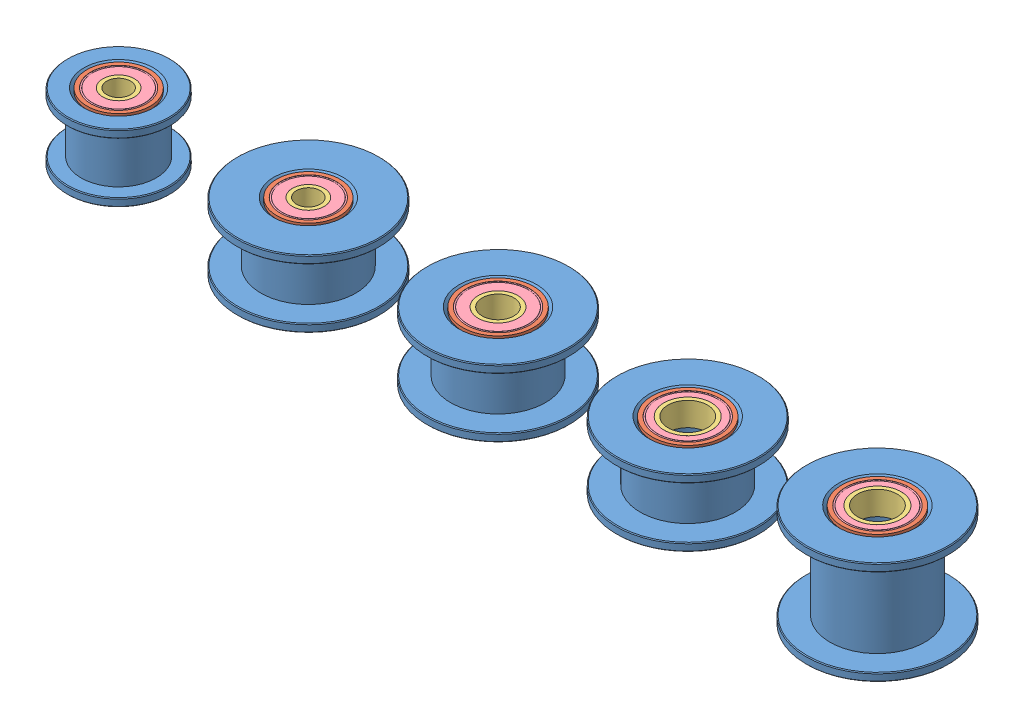
SolidWorks assembly GT2 Idler Pulley, Configurable, Pulleys Lined Up in Assembly, configuration Default. Lengths in mm.
Overall size (117.8 13 25.32).
148 component instances, 5 part files, 0 mates.
Components (placement in the parent):
- GT2 Idler Pulley, Configurable-1: GT2 Idler Pulley, Configurable [16T W6 B3 Without T] at (3.9723 -1.1239 -1.3326) size (18.29 8.5 18.29)
  - Body, GT2 Idler Pulley, Configurable-1: Body, GT2 Idler Pulley, Configurable [16T W6 B3 Without T] x (-0.63029 0 -0.77636) z (0.77636 0 -0.63029) size (13 8.5 13)
  - Bearing Subassy, GT2 Idler Pulley, Configurable-1: Bearing Subassy, GT2 Idler Pulley, Configurable [3 mm Bore] at (0 2.25 0) x (0.63029 0 0.77636) z (-0.77636 0 0.63029) size (8 4 8) (flexible)
    - Bearing Outer Ring, GT2 Idler Pulley, Configurable-1: Bearing Outer Ring, GT2 Idler Pulley, Configurable [3 mm Bore] at origin size (8 4 8)
    - Bearing Inner Ring, GT2 Idler Pulley, Configurable-1: Bearing Inner Ring, GT2 Idler Pulley, Configurable [3 mm Bore] x (0.926062 0 -0.377371) z (0.377371 0 0.926062) size (4 4 4)
    - Bearing Seal, GT2 Idler Pulley, Configurable-1: Bearing Seal, GT2 Idler Pulley, Configurable [3 mm Bore] at (0 1.75 0) size (7 0.5 7)
    - Bearing Seal, GT2 Idler Pulley, Configurable-2: Bearing Seal, GT2 Idler Pulley, Configurable [3 mm Bore] at (0 -1.75 0) x (1 0 0) z (0 0 -1) size (7 0.5 7)
    - Bearing Ball, GT2 Idler Pulley, Configurable-1: Bearing Ball, GT2 Idler Pulley, Configurable [2 mm] at (-1.9442 0 -1.9449) x (-0.715461 0 0.698652) z (-0.698652 0 -0.715461) size (2 2 2)
    - Bearing Ball, GT2 Idler Pulley, Configurable-2: Bearing Ball, GT2 Idler Pulley, Configurable [2 mm] at (0.7122 0 -2.6562) x (-0.962781 0 -0.270282) z (0.270282 0 -0.962781) size (2 2 2)
    - Bearing Ball, GT2 Idler Pulley, Configurable-3: Bearing Ball, GT2 Idler Pulley, Configurable [2 mm] at (2.6564 0 -0.7113) x (-0.24732 0 -0.968934) z (0.968934 0 -0.24732) size (2 2 2)
    - Bearing Ball, GT2 Idler Pulley, Configurable-4: Bearing Ball, GT2 Idler Pulley, Configurable [2 mm] at (1.9442 0 1.9449) x (0.715461 0 -0.698652) z (0.698652 0 0.715461) size (2 2 2)
    - Bearing Ball, GT2 Idler Pulley, Configurable-5: Bearing Ball, GT2 Idler Pulley, Configurable [2 mm] at (-0.7122 0 2.6562) x (0.962781 0 0.270282) z (-0.270282 0 0.962781) size (2 2 2)
    - Bearing Ball, GT2 Idler Pulley, Configurable-6: Bearing Ball, GT2 Idler Pulley, Configurable [2 mm] at (-2.6564 0 0.7113) x (0.24732 0 0.968934) z (-0.968934 0 0.24732) size (2 2 2)
  - Bearing Subassy, GT2 Idler Pulley, Configurable-2: Bearing Subassy, GT2 Idler Pulley, Configurable [3 mm Bore] at (0 -2.25 0) x (0.63029 0 0.77636) z (0.77636 0 -0.63029) size (8 4 8) (flexible)
    - Bearing Outer Ring, GT2 Idler Pulley, Configurable-1: Bearing Outer Ring, GT2 Idler Pulley, Configurable [3 mm Bore] at origin size (8 4 8)
    - Bearing Inner Ring, GT2 Idler Pulley, Configurable-1: Bearing Inner Ring, GT2 Idler Pulley, Configurable [3 mm Bore] x (0.926062 0 -0.377371) z (0.377371 0 0.926062) size (4 4 4)
    - Bearing Seal, GT2 Idler Pulley, Configurable-1: Bearing Seal, GT2 Idler Pulley, Configurable [3 mm Bore] at (0 1.75 0) size (7 0.5 7)
    - Bearing Seal, GT2 Idler Pulley, Configurable-2: Bearing Seal, GT2 Idler Pulley, Configurable [3 mm Bore] at (0 -1.75 0) x (1 0 0) z (0 0 -1) size (7 0.5 7)
    - Bearing Ball, GT2 Idler Pulley, Configurable-1: Bearing Ball, GT2 Idler Pulley, Configurable [2 mm] at (-1.9442 0 -1.9449) x (-0.715461 0 0.698652) z (-0.698652 0 -0.715461) size (2 2 2)
    - Bearing Ball, GT2 Idler Pulley, Configurable-2: Bearing Ball, GT2 Idler Pulley, Configurable [2 mm] at (0.7122 0 -2.6562) x (-0.962781 0 -0.270282) z (0.270282 0 -0.962781) size (2 2 2)
    - Bearing Ball, GT2 Idler Pulley, Configurable-3: Bearing Ball, GT2 Idler Pulley, Configurable [2 mm] at (2.6564 0 -0.7113) x (-0.24732 0 -0.968934) z (0.968934 0 -0.24732) size (2 2 2)
    - Bearing Ball, GT2 Idler Pulley, Configurable-4: Bearing Ball, GT2 Idler Pulley, Configurable [2 mm] at (1.9442 0 1.9449) x (0.715461 0 -0.698652) z (0.698652 0 0.715461) size (2 2 2)
    - Bearing Ball, GT2 Idler Pulley, Configurable-5: Bearing Ball, GT2 Idler Pulley, Configurable [2 mm] at (-0.7122 0 2.6562) x (0.962781 0 0.270282) z (-0.270282 0 0.962781) size (2 2 2)
    - Bearing Ball, GT2 Idler Pulley, Configurable-6: Bearing Ball, GT2 Idler Pulley, Configurable [2 mm] at (-2.6564 0 0.7113) x (0.24732 0 0.968934) z (-0.968934 0 0.24732) size (2 2 2)
- GT2 Idler Pulley, Configurable-3: GT2 Idler Pulley, Configurable [20T W6 B3 Without T] at (27.9723 -1.1239 -1.3326) size (25.32 8.5 25.32)
  - Body, GT2 Idler Pulley, Configurable-1: Body, GT2 Idler Pulley, Configurable [20T W6 B3 Without T] x (-0.63029 0 -0.77636) z (0.77636 0 -0.63029) size (18 8.5 18)
  - Bearing Subassy, GT2 Idler Pulley, Configurable-1: Bearing Subassy, GT2 Idler Pulley, Configurable [3 mm Bore] at (0 2.25 0) x (0.63029 0 0.77636) z (-0.77636 0 0.63029) size (8 4 8) (flexible)
    - Bearing Outer Ring, GT2 Idler Pulley, Configurable-1: Bearing Outer Ring, GT2 Idler Pulley, Configurable [3 mm Bore] at origin size (8 4 8)
    - Bearing Inner Ring, GT2 Idler Pulley, Configurable-1: Bearing Inner Ring, GT2 Idler Pulley, Configurable [3 mm Bore] x (0.926062 0 -0.377371) z (0.377371 0 0.926062) size (4 4 4)
    - Bearing Seal, GT2 Idler Pulley, Configurable-1: Bearing Seal, GT2 Idler Pulley, Configurable [3 mm Bore] at (0 1.75 0) size (7 0.5 7)
    - Bearing Seal, GT2 Idler Pulley, Configurable-2: Bearing Seal, GT2 Idler Pulley, Configurable [3 mm Bore] at (0 -1.75 0) x (1 0 0) z (0 0 -1) size (7 0.5 7)
    - Bearing Ball, GT2 Idler Pulley, Configurable-1: Bearing Ball, GT2 Idler Pulley, Configurable [2 mm] at (-1.9442 0 -1.9449) x (-0.715461 0 0.698652) z (-0.698652 0 -0.715461) size (2 2 2)
    - Bearing Ball, GT2 Idler Pulley, Configurable-2: Bearing Ball, GT2 Idler Pulley, Configurable [2 mm] at (0.7122 0 -2.6562) x (-0.962781 0 -0.270282) z (0.270282 0 -0.962781) size (2 2 2)
    - Bearing Ball, GT2 Idler Pulley, Configurable-3: Bearing Ball, GT2 Idler Pulley, Configurable [2 mm] at (2.6564 0 -0.7113) x (-0.24732 0 -0.968934) z (0.968934 0 -0.24732) size (2 2 2)
    - Bearing Ball, GT2 Idler Pulley, Configurable-4: Bearing Ball, GT2 Idler Pulley, Configurable [2 mm] at (1.9442 0 1.9449) x (0.715461 0 -0.698652) z (0.698652 0 0.715461) size (2 2 2)
    - Bearing Ball, GT2 Idler Pulley, Configurable-5: Bearing Ball, GT2 Idler Pulley, Configurable [2 mm] at (-0.7122 0 2.6562) x (0.962781 0 0.270282) z (-0.270282 0 0.962781) size (2 2 2)
    - Bearing Ball, GT2 Idler Pulley, Configurable-6: Bearing Ball, GT2 Idler Pulley, Configurable [2 mm] at (-2.6564 0 0.7113) x (0.24732 0 0.968934) z (-0.968934 0 0.24732) size (2 2 2)
  - Bearing Subassy, GT2 Idler Pulley, Configurable-2: Bearing Subassy, GT2 Idler Pulley, Configurable [3 mm Bore] at (0 -2.25 0) x (0.63029 0 0.77636) z (0.77636 0 -0.63029) size (8 4 8)
    - Bearing Outer Ring, GT2 Idler Pulley, Configurable-1: Bearing Outer Ring, GT2 Idler Pulley, Configurable [3 mm Bore] at origin size (8 4 8)
    - Bearing Inner Ring, GT2 Idler Pulley, Configurable-1: Bearing Inner Ring, GT2 Idler Pulley, Configurable [3 mm Bore] x (0.926062 0 -0.377371) z (0.377371 0 0.926062) size (4 4 4)
    - Bearing Seal, GT2 Idler Pulley, Configurable-1: Bearing Seal, GT2 Idler Pulley, Configurable [3 mm Bore] at (0 1.75 0) size (7 0.5 7)
    - Bearing Seal, GT2 Idler Pulley, Configurable-2: Bearing Seal, GT2 Idler Pulley, Configurable [3 mm Bore] at (0 -1.75 0) x (1 0 0) z (0 0 -1) size (7 0.5 7)
    - Bearing Ball, GT2 Idler Pulley, Configurable-1: Bearing Ball, GT2 Idler Pulley, Configurable [2 mm] at (-1.9442 0 -1.9449) x (-0.715461 0 0.698652) z (-0.698652 0 -0.715461) size (2 2 2)
    - Bearing Ball, GT2 Idler Pulley, Configurable-2: Bearing Ball, GT2 Idler Pulley, Configurable [2 mm] at (0.7122 0 -2.6562) x (-0.962781 0 -0.270282) z (0.270282 0 -0.962781) size (2 2 2)
    - Bearing Ball, GT2 Idler Pulley, Configurable-3: Bearing Ball, GT2 Idler Pulley, Configurable [2 mm] at (2.6564 0 -0.7113) x (-0.24732 0 -0.968934) z (0.968934 0 -0.24732) size (2 2 2)
    - Bearing Ball, GT2 Idler Pulley, Configurable-4: Bearing Ball, GT2 Idler Pulley, Configurable [2 mm] at (1.9442 0 1.9449) x (0.715461 0 -0.698652) z (0.698652 0 0.715461) size (2 2 2)
    - Bearing Ball, GT2 Idler Pulley, Configurable-5: Bearing Ball, GT2 Idler Pulley, Configurable [2 mm] at (-0.7122 0 2.6562) x (0.962781 0 0.270282) z (-0.270282 0 0.962781) size (2 2 2)
    - Bearing Ball, GT2 Idler Pulley, Configurable-6: Bearing Ball, GT2 Idler Pulley, Configurable [2 mm] at (-2.6564 0 0.7113) x (0.24732 0 0.968934) z (-0.968934 0 0.24732) size (2 2 2)
- GT2 Idler Pulley, Configurable-4: GT2 Idler Pulley, Configurable [20T W6 B4 Without T] at (51.9723 -1.1239 -1.3326) size (25.32 8.5 25.32)
  - Body, GT2 Idler Pulley, Configurable-1: Body, GT2 Idler Pulley, Configurable [20T W6 B4 Without T] x (-0.63029 0 -0.77636) z (0.77636 0 -0.63029) size (18 8.5 18)
  - Bearing Subassy, GT2 Idler Pulley, Configurable-1: Bearing Subassy, GT2 Idler Pulley, Configurable [4 mm Bore] at (0 2.25 0) x (0.63029 0 0.77636) z (-0.77636 0 0.63029) size (9 4 9) (flexible)
    - Bearing Outer Ring, GT2 Idler Pulley, Configurable-1: Bearing Outer Ring, GT2 Idler Pulley, Configurable [4 mm Bore] at origin size (9 4 9)
    - Bearing Inner Ring, GT2 Idler Pulley, Configurable-1: Bearing Inner Ring, GT2 Idler Pulley, Configurable [4 mm Bore] x (0.926062 0 -0.377371) z (0.377371 0 0.926062) size (5 4 5)
    - Bearing Seal, GT2 Idler Pulley, Configurable-1: Bearing Seal, GT2 Idler Pulley, Configurable [4 mm Bore] at (0 1.75 0) size (8 0.5 8)
    - Bearing Seal, GT2 Idler Pulley, Configurable-2: Bearing Seal, GT2 Idler Pulley, Configurable [4 mm Bore] at (0 -1.75 0) x (1 0 0) z (0 0 -1) size (8 0.5 8)
    - Bearing Ball, GT2 Idler Pulley, Configurable-1: Bearing Ball, GT2 Idler Pulley, Configurable [2 mm] at (-2.2988 0 -2.2974) x (-0.715461 0 0.698652) z (-0.698652 0 -0.715461) size (2 2 2)
    - Bearing Ball, GT2 Idler Pulley, Configurable-2: Bearing Ball, GT2 Idler Pulley, Configurable [2 mm] at (-0.001 0 -3.25) x (-0.999929 0 -0.011886) z (0.011886 0 -0.999929) size (2 2 2)
    - Bearing Ball, GT2 Idler Pulley, Configurable-3: Bearing Ball, GT2 Idler Pulley, Configurable [2 mm] at (2.2974 0 -2.2988) x (-0.698652 0 -0.715461) z (0.715461 0 -0.698652) size (2 2 2)
    - Bearing Ball, GT2 Idler Pulley, Configurable-4: Bearing Ball, GT2 Idler Pulley, Configurable [2 mm] at (3.25 0 -0.001) x (0.011886 0 -0.999929) z (0.999929 0 0.011886) size (2 2 2)
    - Bearing Ball, GT2 Idler Pulley, Configurable-5: Bearing Ball, GT2 Idler Pulley, Configurable [2 mm] at (2.2988 0 2.2974) x (0.715461 0 -0.698652) z (0.698652 0 0.715461) size (2 2 2)
    - Bearing Ball, GT2 Idler Pulley, Configurable-6: Bearing Ball, GT2 Idler Pulley, Configurable [2 mm] at (0.001 0 3.25) x (0.999929 0 0.011886) z (-0.011886 0 0.999929) size (2 2 2)
    - Bearing Ball, GT2 Idler Pulley, Configurable-7: Bearing Ball, GT2 Idler Pulley, Configurable [2 mm] at (-2.2974 0 2.2988) x (0.698652 0 0.715461) z (-0.715461 0 0.698652) size (2 2 2)
    - Bearing Ball, GT2 Idler Pulley, Configurable-8: Bearing Ball, GT2 Idler Pulley, Configurable [2 mm] at (-3.25 0 0.001) x (-0.011886 0 0.999929) z (-0.999929 0 -0.011886) size (2 2 2)
  - Bearing Subassy, GT2 Idler Pulley, Configurable-2: Bearing Subassy, GT2 Idler Pulley, Configurable [4 mm Bore] at (0 -2.25 0) x (0.63029 0 0.77636) z (0.77636 0 -0.63029) size (9 4 9) (flexible)
    - Bearing Outer Ring, GT2 Idler Pulley, Configurable-1: Bearing Outer Ring, GT2 Idler Pulley, Configurable [4 mm Bore] at origin size (9 4 9)
    - Bearing Inner Ring, GT2 Idler Pulley, Configurable-1: Bearing Inner Ring, GT2 Idler Pulley, Configurable [4 mm Bore] x (0.926062 0 -0.377371) z (0.377371 0 0.926062) size (5 4 5)
    - Bearing Seal, GT2 Idler Pulley, Configurable-1: Bearing Seal, GT2 Idler Pulley, Configurable [4 mm Bore] at (0 1.75 0) size (8 0.5 8)
    - Bearing Seal, GT2 Idler Pulley, Configurable-2: Bearing Seal, GT2 Idler Pulley, Configurable [4 mm Bore] at (0 -1.75 0) x (1 0 0) z (0 0 -1) size (8 0.5 8)
    - Bearing Ball, GT2 Idler Pulley, Configurable-1: Bearing Ball, GT2 Idler Pulley, Configurable [2 mm] at (-2.2988 0 -2.2974) x (-0.715461 0 0.698652) z (-0.698652 0 -0.715461) size (2 2 2)
    - Bearing Ball, GT2 Idler Pulley, Configurable-2: Bearing Ball, GT2 Idler Pulley, Configurable [2 mm] at (-0.001 0 -3.25) x (-0.999929 0 -0.011886) z (0.011886 0 -0.999929) size (2 2 2)
    - Bearing Ball, GT2 Idler Pulley, Configurable-3: Bearing Ball, GT2 Idler Pulley, Configurable [2 mm] at (2.2974 0 -2.2988) x (-0.698652 0 -0.715461) z (0.715461 0 -0.698652) size (2 2 2)
    - Bearing Ball, GT2 Idler Pulley, Configurable-4: Bearing Ball, GT2 Idler Pulley, Configurable [2 mm] at (3.25 0 -0.001) x (0.011886 0 -0.999929) z (0.999929 0 0.011886) size (2 2 2)
    - Bearing Ball, GT2 Idler Pulley, Configurable-5: Bearing Ball, GT2 Idler Pulley, Configurable [2 mm] at (2.2988 0 2.2974) x (0.715461 0 -0.698652) z (0.698652 0 0.715461) size (2 2 2)
    - Bearing Ball, GT2 Idler Pulley, Configurable-6: Bearing Ball, GT2 Idler Pulley, Configurable [2 mm] at (0.001 0 3.25) x (0.999929 0 0.011886) z (-0.011886 0 0.999929) size (2 2 2)
    - Bearing Ball, GT2 Idler Pulley, Configurable-7: Bearing Ball, GT2 Idler Pulley, Configurable [2 mm] at (-2.2974 0 2.2988) x (0.698652 0 0.715461) z (-0.715461 0 0.698652) size (2 2 2)
    - Bearing Ball, GT2 Idler Pulley, Configurable-8: Bearing Ball, GT2 Idler Pulley, Configurable [2 mm] at (-3.25 0 0.001) x (-0.011886 0 0.999929) z (-0.999929 0 -0.011886) size (2 2 2)
- GT2 Idler Pulley, Configurable-5: GT2 Idler Pulley, Configurable [20T W6 B5 Without T] at (75.9723 -1.1239 -1.3326) size (25.32 8.5 25.32)
  - Body, GT2 Idler Pulley, Configurable-1: Body, GT2 Idler Pulley, Configurable [20T W6 B5 Without T] x (-0.63029 0 -0.77636) z (0.77636 0 -0.63029) size (18 8.5 18)
  - Bearing Subassy, GT2 Idler Pulley, Configurable-1: Bearing Subassy, GT2 Idler Pulley, Configurable [5 mm Bore] at (0 2.75 0) x (0.63029 0 0.77636) z (-0.77636 0 0.63029) size (9 3 9)
    - Bearing Outer Ring, GT2 Idler Pulley, Configurable-1: Bearing Outer Ring, GT2 Idler Pulley, Configurable [5 mm Bore] at origin size (9 3 9)
    - Bearing Inner Ring, GT2 Idler Pulley, Configurable-1: Bearing Inner Ring, GT2 Idler Pulley, Configurable [5 mm Bore] x (0.926062 0 -0.377371) z (0.377371 0 0.926062) size (6 3 6)
    - Bearing Seal, GT2 Idler Pulley, Configurable-1: Bearing Seal, GT2 Idler Pulley, Configurable [5 mm Bore] at (0 1.25 0) size (8 0.5 8)
    - Bearing Seal, GT2 Idler Pulley, Configurable-2: Bearing Seal, GT2 Idler Pulley, Configurable [5 mm Bore] at (0 -1.25 0) x (1 0 0) z (0 0 -1) size (8 0.5 8)
    - Bearing Ball, GT2 Idler Pulley, Configurable-1: Bearing Ball, GT2 Idler Pulley, Configurable [1.4 mm] at (-2.4745 0 -2.4753) x (-0.715461 0 0.698652) z (-0.698652 0 -0.715461) size (1.4 1.4 1.4)
    - Bearing Ball, GT2 Idler Pulley, Configurable-2: Bearing Ball, GT2 Idler Pulley, Configurable [1.4 mm] at (-0.9053 0 -3.3809) x (-0.968934 0 0.24732) z (-0.24732 0 -0.968934) size (1.4 1.4 1.4)
    - Bearing Ball, GT2 Idler Pulley, Configurable-3: Bearing Ball, GT2 Idler Pulley, Configurable [1.4 mm] at (0.9064 0 -3.3806) x (-0.962781 0 -0.270282) z (0.270282 0 -0.962781) size (1.4 1.4 1.4)
    - Bearing Ball, GT2 Idler Pulley, Configurable-4: Bearing Ball, GT2 Idler Pulley, Configurable [1.4 mm] at (2.4753 0 -2.4745) x (-0.698652 0 -0.715461) z (0.715461 0 -0.698652) size (1.4 1.4 1.4)
    - Bearing Ball, GT2 Idler Pulley, Configurable-5: Bearing Ball, GT2 Idler Pulley, Configurable [1.4 mm] at (3.3809 0 -0.9053) x (-0.24732 0 -0.968934) z (0.968934 0 -0.24732) size (1.4 1.4 1.4)
    - Bearing Ball, GT2 Idler Pulley, Configurable-6: Bearing Ball, GT2 Idler Pulley, Configurable [1.4 mm] at (3.3806 0 0.9064) x (0.270282 0 -0.962781) z (0.962781 0 0.270282) size (1.4 1.4 1.4)
    - Bearing Ball, GT2 Idler Pulley, Configurable-7: Bearing Ball, GT2 Idler Pulley, Configurable [1.4 mm] at (2.4745 0 2.4753) x (0.715461 0 -0.698652) z (0.698652 0 0.715461) size (1.4 1.4 1.4)
    - Bearing Ball, GT2 Idler Pulley, Configurable-8: Bearing Ball, GT2 Idler Pulley, Configurable [1.4 mm] at (0.9053 0 3.3809) x (0.968934 0 -0.24732) z (0.24732 0 0.968934) size (1.4 1.4 1.4)
    - Bearing Ball, GT2 Idler Pulley, Configurable-9: Bearing Ball, GT2 Idler Pulley, Configurable [1.4 mm] at (-0.9064 0 3.3806) x (0.962781 0 0.270282) z (-0.270282 0 0.962781) size (1.4 1.4 1.4)
    - Bearing Ball, GT2 Idler Pulley, Configurable-10: Bearing Ball, GT2 Idler Pulley, Configurable [1.4 mm] at (-2.4753 0 2.4745) x (0.698652 0 0.715461) z (-0.715461 0 0.698652) size (1.4 1.4 1.4)
    - Bearing Ball, GT2 Idler Pulley, Configurable-11: Bearing Ball, GT2 Idler Pulley, Configurable [1.4 mm] at (-3.3809 0 0.9053) x (0.24732 0 0.968934) z (-0.968934 0 0.24732) size (1.4 1.4 1.4)
    - Bearing Ball, GT2 Idler Pulley, Configurable-12: Bearing Ball, GT2 Idler Pulley, Configurable [1.4 mm] at (-3.3806 0 -0.9064) x (-0.270282 0 0.962781) z (-0.962781 0 -0.270282) size (1.4 1.4 1.4)
  - Bearing Subassy, GT2 Idler Pulley, Configurable-2: Bearing Subassy, GT2 Idler Pulley, Configurable [5 mm Bore] at (0 -2.75 0) x (0.63029 0 0.77636) z (0.77636 0 -0.63029) size (9 3 9)
    - Bearing Outer Ring, GT2 Idler Pulley, Configurable-1: Bearing Outer Ring, GT2 Idler Pulley, Configurable [5 mm Bore] at origin size (9 3 9)
    - Bearing Inner Ring, GT2 Idler Pulley, Configurable-1: Bearing Inner Ring, GT2 Idler Pulley, Configurable [5 mm Bore] x (0.926062 0 -0.377371) z (0.377371 0 0.926062) size (6 3 6)
    - Bearing Seal, GT2 Idler Pulley, Configurable-1: Bearing Seal, GT2 Idler Pulley, Configurable [5 mm Bore] at (0 1.25 0) size (8 0.5 8)
    - Bearing Seal, GT2 Idler Pulley, Configurable-2: Bearing Seal, GT2 Idler Pulley, Configurable [5 mm Bore] at (0 -1.25 0) x (1 0 0) z (0 0 -1) size (8 0.5 8)
    - Bearing Ball, GT2 Idler Pulley, Configurable-1: Bearing Ball, GT2 Idler Pulley, Configurable [1.4 mm] at (-2.4745 0 -2.4753) x (-0.715461 0 0.698652) z (-0.698652 0 -0.715461) size (1.4 1.4 1.4)
    - Bearing Ball, GT2 Idler Pulley, Configurable-2: Bearing Ball, GT2 Idler Pulley, Configurable [1.4 mm] at (-0.9053 0 -3.3809) x (-0.968934 0 0.24732) z (-0.24732 0 -0.968934) size (1.4 1.4 1.4)
    - Bearing Ball, GT2 Idler Pulley, Configurable-3: Bearing Ball, GT2 Idler Pulley, Configurable [1.4 mm] at (0.9064 0 -3.3806) x (-0.962781 0 -0.270282) z (0.270282 0 -0.962781) size (1.4 1.4 1.4)
    - Bearing Ball, GT2 Idler Pulley, Configurable-4: Bearing Ball, GT2 Idler Pulley, Configurable [1.4 mm] at (2.4753 0 -2.4745) x (-0.698652 0 -0.715461) z (0.715461 0 -0.698652) size (1.4 1.4 1.4)
    - Bearing Ball, GT2 Idler Pulley, Configurable-5: Bearing Ball, GT2 Idler Pulley, Configurable [1.4 mm] at (3.3809 0 -0.9053) x (-0.24732 0 -0.968934) z (0.968934 0 -0.24732) size (1.4 1.4 1.4)
    - Bearing Ball, GT2 Idler Pulley, Configurable-6: Bearing Ball, GT2 Idler Pulley, Configurable [1.4 mm] at (3.3806 0 0.9064) x (0.270282 0 -0.962781) z (0.962781 0 0.270282) size (1.4 1.4 1.4)
    - Bearing Ball, GT2 Idler Pulley, Configurable-7: Bearing Ball, GT2 Idler Pulley, Configurable [1.4 mm] at (2.4745 0 2.4753) x (0.715461 0 -0.698652) z (0.698652 0 0.715461) size (1.4 1.4 1.4)
    - Bearing Ball, GT2 Idler Pulley, Configurable-8: Bearing Ball, GT2 Idler Pulley, Configurable [1.4 mm] at (0.9053 0 3.3809) x (0.968934 0 -0.24732) z (0.24732 0 0.968934) size (1.4 1.4 1.4)
    - Bearing Ball, GT2 Idler Pulley, Configurable-9: Bearing Ball, GT2 Idler Pulley, Configurable [1.4 mm] at (-0.9064 0 3.3806) x (0.962781 0 0.270282) z (-0.270282 0 0.962781) size (1.4 1.4 1.4)
    - Bearing Ball, GT2 Idler Pulley, Configurable-10: Bearing Ball, GT2 Idler Pulley, Configurable [1.4 mm] at (-2.4753 0 2.4745) x (0.698652 0 0.715461) z (-0.715461 0 0.698652) size (1.4 1.4 1.4)
    - Bearing Ball, GT2 Idler Pulley, Configurable-11: Bearing Ball, GT2 Idler Pulley, Configurable [1.4 mm] at (-3.3809 0 0.9053) x (0.24732 0 0.968934) z (-0.968934 0 0.24732) size (1.4 1.4 1.4)
    - Bearing Ball, GT2 Idler Pulley, Configurable-12: Bearing Ball, GT2 Idler Pulley, Configurable [1.4 mm] at (-3.3806 0 -0.9064) x (-0.270282 0 0.962781) z (-0.962781 0 -0.270282) size (1.4 1.4 1.4)
- GT2 Idler Pulley, Configurable-6: GT2 Idler Pulley, Configurable [20T W10 B5 Without T] at (99.9723 -1.1239 -1.3326) size (25.32 13 25.32)
  - Body, GT2 Idler Pulley, Configurable-1: Body, GT2 Idler Pulley, Configurable [20T W10 B5 Without T] x (-0.63029 0 -0.77636) z (0.77636 0 -0.63029) size (18 13 18)
  - Bearing Subassy, GT2 Idler Pulley, Configurable-1: Bearing Subassy, GT2 Idler Pulley, Configurable [5 mm Bore] at (0 5 0) x (0.63029 0 0.77636) z (-0.77636 0 0.63029) size (9 3 9) (flexible)
    - Bearing Outer Ring, GT2 Idler Pulley, Configurable-1: Bearing Outer Ring, GT2 Idler Pulley, Configurable [5 mm Bore] at origin size (9 3 9)
    - Bearing Inner Ring, GT2 Idler Pulley, Configurable-1: Bearing Inner Ring, GT2 Idler Pulley, Configurable [5 mm Bore] x (0.926062 0 -0.377371) z (0.377371 0 0.926062) size (6 3 6)
    - Bearing Seal, GT2 Idler Pulley, Configurable-1: Bearing Seal, GT2 Idler Pulley, Configurable [5 mm Bore] at (0 1.25 0) size (8 0.5 8)
    - Bearing Seal, GT2 Idler Pulley, Configurable-2: Bearing Seal, GT2 Idler Pulley, Configurable [5 mm Bore] at (0 -1.25 0) x (1 0 0) z (0 0 -1) size (8 0.5 8)
    - Bearing Ball, GT2 Idler Pulley, Configurable-1: Bearing Ball, GT2 Idler Pulley, Configurable [1.4 mm] at (-2.4755 0 -2.4742) x (-0.715461 0 0.698652) z (-0.698652 0 -0.715461) size (1.4 1.4 1.4)
    - Bearing Ball, GT2 Idler Pulley, Configurable-2: Bearing Ball, GT2 Idler Pulley, Configurable [1.4 mm] at (-0.9068 0 -3.3805) x (-0.968934 0 0.24732) z (-0.24732 0 -0.968934) size (1.4 1.4 1.4)
    - Bearing Ball, GT2 Idler Pulley, Configurable-3: Bearing Ball, GT2 Idler Pulley, Configurable [1.4 mm] at (0.905 0 -3.381) x (-0.962781 0 -0.270282) z (0.270282 0 -0.962781) size (1.4 1.4 1.4)
    - Bearing Ball, GT2 Idler Pulley, Configurable-4: Bearing Ball, GT2 Idler Pulley, Configurable [1.4 mm] at (2.4742 0 -2.4755) x (-0.698652 0 -0.715461) z (0.715461 0 -0.698652) size (1.4 1.4 1.4)
    - Bearing Ball, GT2 Idler Pulley, Configurable-5: Bearing Ball, GT2 Idler Pulley, Configurable [1.4 mm] at (3.3805 0 -0.9068) x (-0.24732 0 -0.968934) z (0.968934 0 -0.24732) size (1.4 1.4 1.4)
    - Bearing Ball, GT2 Idler Pulley, Configurable-6: Bearing Ball, GT2 Idler Pulley, Configurable [1.4 mm] at (3.381 0 0.905) x (0.270282 0 -0.962781) z (0.962781 0 0.270282) size (1.4 1.4 1.4)
    - Bearing Ball, GT2 Idler Pulley, Configurable-7: Bearing Ball, GT2 Idler Pulley, Configurable [1.4 mm] at (2.4755 0 2.4742) x (0.715461 0 -0.698652) z (0.698652 0 0.715461) size (1.4 1.4 1.4)
    - Bearing Ball, GT2 Idler Pulley, Configurable-8: Bearing Ball, GT2 Idler Pulley, Configurable [1.4 mm] at (0.9068 0 3.3805) x (0.968934 0 -0.24732) z (0.24732 0 0.968934) size (1.4 1.4 1.4)
    - Bearing Ball, GT2 Idler Pulley, Configurable-9: Bearing Ball, GT2 Idler Pulley, Configurable [1.4 mm] at (-0.905 0 3.381) x (0.962781 0 0.270282) z (-0.270282 0 0.962781) size (1.4 1.4 1.4)
    - Bearing Ball, GT2 Idler Pulley, Configurable-10: Bearing Ball, GT2 Idler Pulley, Configurable [1.4 mm] at (-2.4742 0 2.4755) x (0.698652 0 0.715461) z (-0.715461 0 0.698652) size (1.4 1.4 1.4)
    - Bearing Ball, GT2 Idler Pulley, Configurable-11: Bearing Ball, GT2 Idler Pulley, Configurable [1.4 mm] at (-3.3805 0 0.9068) x (0.24732 0 0.968934) z (-0.968934 0 0.24732) size (1.4 1.4 1.4)
    - Bearing Ball, GT2 Idler Pulley, Configurable-12: Bearing Ball, GT2 Idler Pulley, Configurable [1.4 mm] at (-3.381 0 -0.905) x (-0.270282 0 0.962781) z (-0.962781 0 -0.270282) size (1.4 1.4 1.4)
  - Bearing Subassy, GT2 Idler Pulley, Configurable-2: Bearing Subassy, GT2 Idler Pulley, Configurable [5 mm Bore] at (0 -5 0) x (0.63029 0 0.77636) z (0.77636 0 -0.63029) size (9 3 9) (flexible)
    - Bearing Outer Ring, GT2 Idler Pulley, Configurable-1: Bearing Outer Ring, GT2 Idler Pulley, Configurable [5 mm Bore] at origin size (9 3 9)
    - Bearing Inner Ring, GT2 Idler Pulley, Configurable-1: Bearing Inner Ring, GT2 Idler Pulley, Configurable [5 mm Bore] x (0.926062 0 -0.377371) z (0.377371 0 0.926062) size (6 3 6)
    - Bearing Seal, GT2 Idler Pulley, Configurable-1: Bearing Seal, GT2 Idler Pulley, Configurable [5 mm Bore] at (0 1.25 0) size (8 0.5 8)
    - Bearing Seal, GT2 Idler Pulley, Configurable-2: Bearing Seal, GT2 Idler Pulley, Configurable [5 mm Bore] at (0 -1.25 0) x (1 0 0) z (0 0 -1) size (8 0.5 8)
    - Bearing Ball, GT2 Idler Pulley, Configurable-1: Bearing Ball, GT2 Idler Pulley, Configurable [1.4 mm] at (-2.4755 0 -2.4742) x (-0.715461 0 0.698652) z (-0.698652 0 -0.715461) size (1.4 1.4 1.4)
    - Bearing Ball, GT2 Idler Pulley, Configurable-2: Bearing Ball, GT2 Idler Pulley, Configurable [1.4 mm] at (-0.9068 0 -3.3805) x (-0.968934 0 0.24732) z (-0.24732 0 -0.968934) size (1.4 1.4 1.4)
    - Bearing Ball, GT2 Idler Pulley, Configurable-3: Bearing Ball, GT2 Idler Pulley, Configurable [1.4 mm] at (0.905 0 -3.381) x (-0.962781 0 -0.270282) z (0.270282 0 -0.962781) size (1.4 1.4 1.4)
    - Bearing Ball, GT2 Idler Pulley, Configurable-4: Bearing Ball, GT2 Idler Pulley, Configurable [1.4 mm] at (2.4742 0 -2.4755) x (-0.698652 0 -0.715461) z (0.715461 0 -0.698652) size (1.4 1.4 1.4)
    - Bearing Ball, GT2 Idler Pulley, Configurable-5: Bearing Ball, GT2 Idler Pulley, Configurable [1.4 mm] at (3.3805 0 -0.9068) x (-0.24732 0 -0.968934) z (0.968934 0 -0.24732) size (1.4 1.4 1.4)
    - Bearing Ball, GT2 Idler Pulley, Configurable-6: Bearing Ball, GT2 Idler Pulley, Configurable [1.4 mm] at (3.381 0 0.905) x (0.270282 0 -0.962781) z (0.962781 0 0.270282) size (1.4 1.4 1.4)
    - Bearing Ball, GT2 Idler Pulley, Configurable-7: Bearing Ball, GT2 Idler Pulley, Configurable [1.4 mm] at (2.4755 0 2.4742) x (0.715461 0 -0.698652) z (0.698652 0 0.715461) size (1.4 1.4 1.4)
    - Bearing Ball, GT2 Idler Pulley, Configurable-8: Bearing Ball, GT2 Idler Pulley, Configurable [1.4 mm] at (0.9068 0 3.3805) x (0.968934 0 -0.24732) z (0.24732 0 0.968934) size (1.4 1.4 1.4)
    - Bearing Ball, GT2 Idler Pulley, Configurable-9: Bearing Ball, GT2 Idler Pulley, Configurable [1.4 mm] at (-0.905 0 3.381) x (0.962781 0 0.270282) z (-0.270282 0 0.962781) size (1.4 1.4 1.4)
    - Bearing Ball, GT2 Idler Pulley, Configurable-10: Bearing Ball, GT2 Idler Pulley, Configurable [1.4 mm] at (-2.4742 0 2.4755) x (0.698652 0 0.715461) z (-0.715461 0 0.698652) size (1.4 1.4 1.4)
    - Bearing Ball, GT2 Idler Pulley, Configurable-11: Bearing Ball, GT2 Idler Pulley, Configurable [1.4 mm] at (-3.3805 0 0.9068) x (0.24732 0 0.968934) z (-0.968934 0 0.24732) size (1.4 1.4 1.4)
    - Bearing Ball, GT2 Idler Pulley, Configurable-12: Bearing Ball, GT2 Idler Pulley, Configurable [1.4 mm] at (-3.381 0 -0.905) x (-0.270282 0 0.962781) z (-0.962781 0 -0.270282) size (1.4 1.4 1.4)
